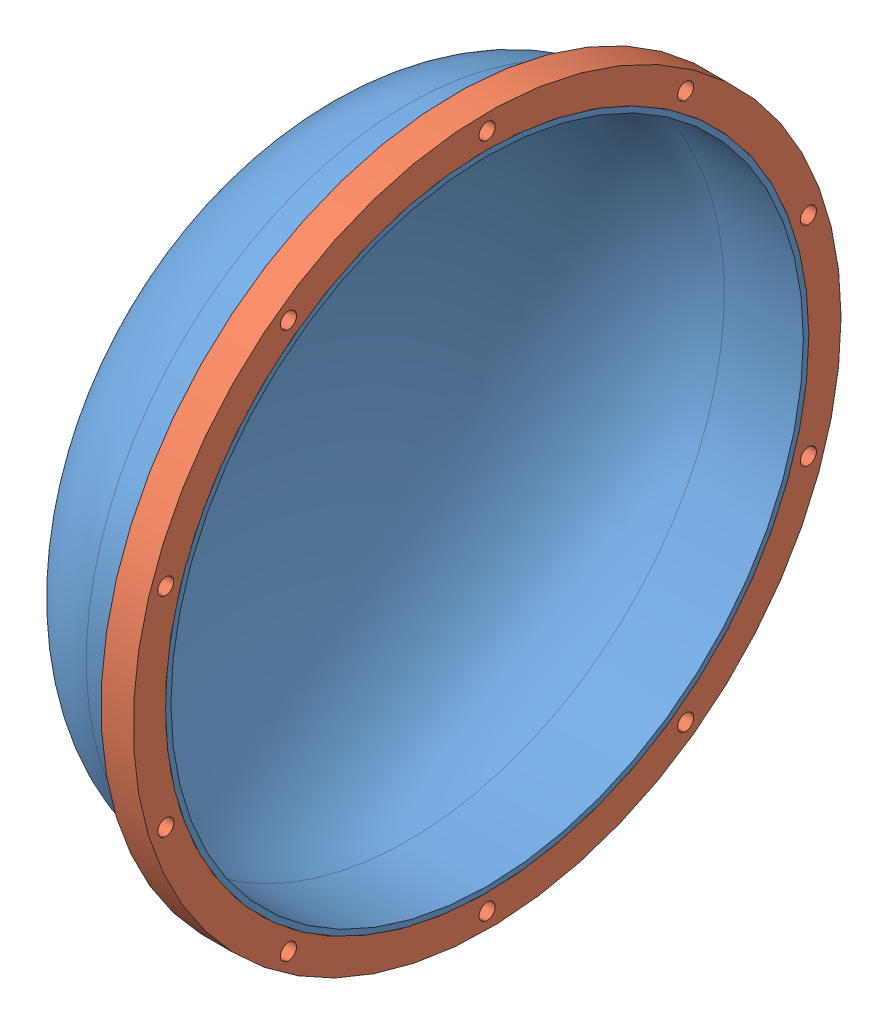
SolidWorks assembly Сборка1, configuration Default. Lengths in mm.
Overall size (88.25 257.4 257.4).
2 component instances, 2 part files, 2 mates.
Components (placement in the parent):
- кришка1-1: кришка1 [По умолчанию] at (19.1241 155.0338 201.3627) size (88.25 234 234)
- флянець-1: флянець [По умолчанию] at (47.8741 155.0338 201.3627) x (0 0 -1) z (1 0 0) size (257.4 257.4 11.7)
Mates (geometry in assembly coordinates):
- Концентричный1: concentric: circle of кришка1-1; circle of флянець-1
- Совпадение2: coincident anti-aligned: circle of кришка1-1; circle of флянець-1
